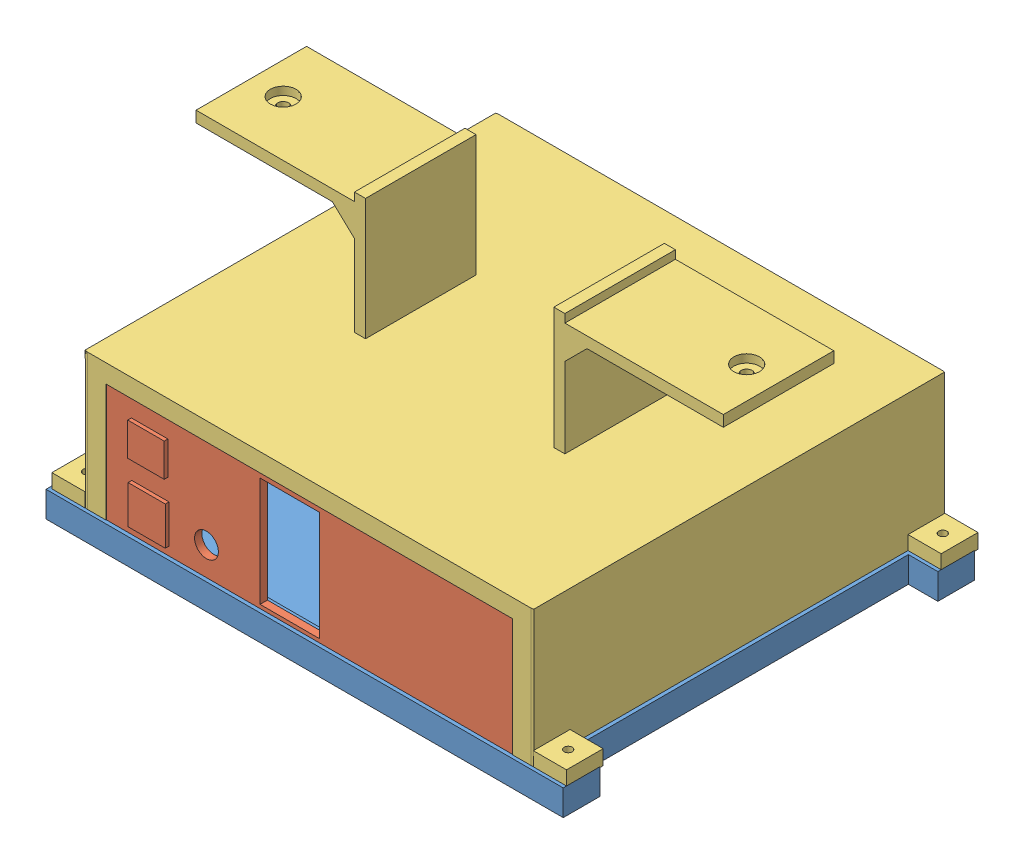
SolidWorks assembly AssemBox, configuration Default. Lengths in mm.
Overall size (143.12 77 112.59).
3 component instances, 3 part files, 4 mates.
Components (placement in the parent):
- bunn-2: bunn [Default] at (-13.5567 53.791 158.6943) size (140.4 42 111.7)
- side-2: side [Default] at (-8.051 65.941 157.6943) size (114.3 37.8 3)
- topp-1: topp [Default] at (-13.2067 106.441 46.1007) x (1 0 0) z (0 0 -1) size (143.12 73.5 111.7)
Mates (geometry in assembly coordinates):
- Coincident1: coincident anti-aligned: plane of bunn-2 through (-13.5567 65.941 158.6943) normal (0 1 0); plane of side-2 through (-8.051 65.941 157.6943) normal (0 -1 0)
- Coincident2: coincident anti-aligned: plane of bunn-2 through (-8.7067 65.941 157.6943) normal (0 0 -1); plane of side-2 through (-8.051 103.741 157.6943) normal (0 0 1)
- Coincident3: coincident anti-aligned: plane of bunn-2 through (-13.5567 65.941 158.6943) normal (0 1 0); plane of topp-1 through (-13.2067 65.941 46.1007) normal (0 -1 0)
- Coincident4: coincident anti-aligned: plane of bunn-2 through (109.8433 65.941 153.9943) normal (-1 0 0); plane of topp-1 through (109.8433 65.941 51.1007) normal (1 0 0)
